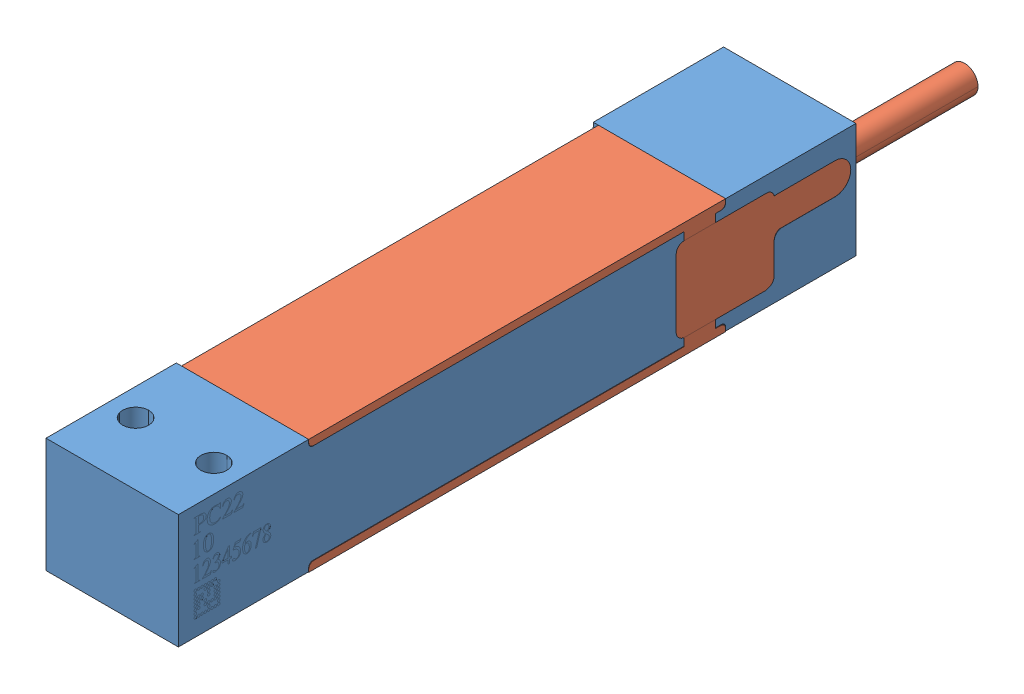
SolidWorks assembly PC22 5kg...10kg outline assembly, configuration Défaut. Lengths in mm.
Overall size (25.4 22.1 155).
3 component instances, 2 part files, 0 mates.
Components (placement in the parent):
- PC22 5kg...10kg outline assembly.STEP-1: PC22 5kg...10kg outline assembly.STEP [Défaut] at origin size (25.4 22.1 155)
  - 0008756.STEP-1: 0008756.STEP [Défaut] at (-7.9662 -11.4939 5.3108) size (25.4 22 130)
  - 0020069_con fig 1.STEP-1: 0020069_con fig 1.STEP [Défaut] at (10.6338 -228.1083 229.2135) x (0 0 -1) z (1 0 0) size (130 22.1 24.4)
